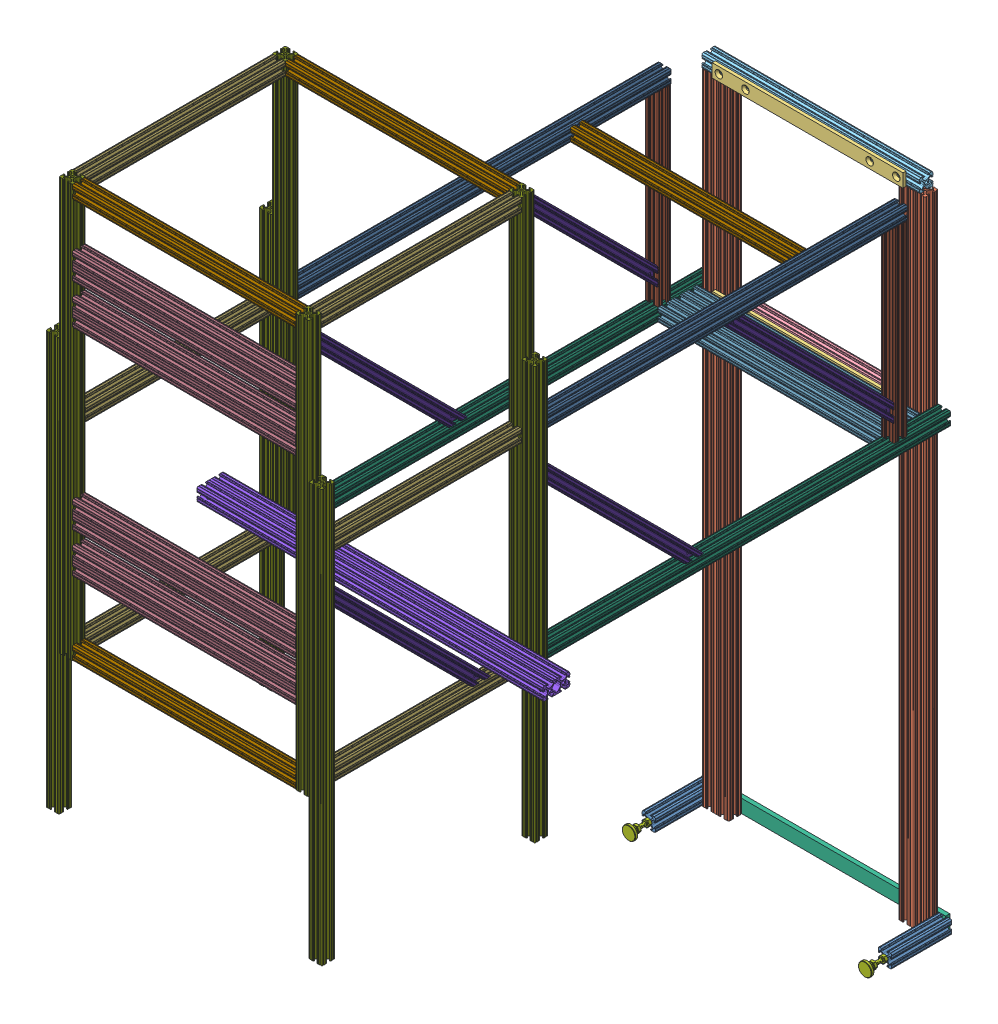
SolidWorks assembly FEA - _Tow System Assy V1.1, configuration Default. Lengths in mm.
Overall size (660.4 1633.42 1235.21).
46 component instances, 17 part files, 141 mates.
Components (placement in the parent):
- FEA - 8020 -1inch - 0 ft 4.5 in-1: FEA - 8020 -1inch - 0 ft 4.5 in [47065T122] at (0 -1222.37 -954.22) x (-1 0 0) z (0 0 1) size (25.4 25.4 114.3)
- FEA - 8020 -1inch - 0 ft 4.5 in-2: FEA - 8020 -1inch - 0 ft 4.5 in [47065T122] at (450.85 -1222.37 -954.22) x (-1 0 0) z (0 0 1) size (25.4 25.4 114.3)
- FEA - 47065T125_2inch - 4 ft-1: FEA - 47065T125_2inch - 4 ft [47065T125] at (38.1 -625.47 -998.67) x (1 0 0) z (0 1 0) size (50.8 25.4 1219.2)
- FEA - 47065T125_2inch - 4 ft-2: FEA - 47065T125_2inch - 4 ft [47065T125] at (412.75 -625.47 -998.67) x (1 0 0) z (0 1 0) size (50.8 25.4 1219.2)
- FEA - 1614T644_1in x 364mm Aluminium bar - 5_16 thick-1: FEA - 1614T644_1in x 364mm Aluminium bar - 5_16 thick [1614T644] at (220.1 -381 -982.97) x (0 -1 0) z (-1 0 0) size (25.4 6 364)
- FEA - 1614T644_1in x 364mm Aluminium bar - 5_16 thick-2: FEA - 1614T644_1in x 364mm Aluminium bar - 5_16 thick [1614T644] at (220.1 -3.17 -982.97) x (0 1 0) z (1 0 0) size (25.4 6 364)
- FEA - 8020 -1inch - 1 ft 0.25-3: FEA - 8020 -1inch - 1 ft 0.25 [47065T122] at (219.075 -381 -998.67) x (0 0 -1) z (1 0 0) size (25.4 25.4 311.15)
- FEA - 8020 -1inch - 415mm-1: FEA - 8020 -1inch - 415mm [47065T122] at (220.2 -3.17 -998.67) x (0 0 -1) z (1 0 0) size (25.4 25.4 415)
- FEA - 1614T644_1in x 465mm Aluminium bar - 5_16 thick-1: FEA - 1614T644_1in x 465mm Aluminium bar - 5_16 thick [1614T644] at (219.8 -1222.37 -1015.3388) x (0 -1 0) z (-1 0 0) size (25.4 7.94 465)
- FEA - 6111K115_SS Leveling Foot-3: FEA - 6111K115_SS Leveling Foot [6111K115] at (0 -1222.37 -858.4408) x (-0.866025 0.5 0) z (-0.5 -0.866025 0) size (25.4 81.68 25.4)
- FEA - 6111K115_SS Leveling Foot-4: FEA - 6111K115_SS Leveling Foot [6111K115] at (450.85 -1222.37 -858.4408) x (0.866025 0.5 0) z (-0.5 0.866025 0) size (25.4 81.68 25.4)
- FEA - 8020 - 2inch - 2 ft 2 in-1: FEA - 8020 - 2inch - 2 ft 2 in [47065T213] at (225.425 -355.6 -165.1) x (0 0 1) z (-1 0 0) size (50.8 25.4 660.4)
- FEA - 8020 -1inch - 1 ft 4.75 in-9: FEA - 8020 -1inch - 1 ft 4.75 in [47065T122] at (225.425 -381 203.2) x (0 -1 0) z (1 0 0) size (25.4 25.4 425.45)
- FEA - 8020 -1inch - 2 ft 4 in-13: FEA - 8020 -1inch - 2 ft 4 in [47065T122] at (0 0 -571.5) x (-1 0 0) z (0 0 -1) size (25.4 25.4 711.2)
- FEA - 8020 -1inch - 2 ft 4 in-14: FEA - 8020 -1inch - 2 ft 4 in [47065T122] at (450.85 0 -571.5) x (-1 0 0) z (0 0 -1) size (25.4 25.4 711.2)
- FEA - 8020 -1inch - 1 ft 2 in-1: FEA - 8020 -1inch - 1 ft 2 in [47065T122] at (0 -190.5 -914.4) x (1 0 0) z (0 1 0) size (25.4 25.4 355.6)
- FEA - 8020 -1inch - 1 ft 3 in-2: FEA - 8020 -1inch - 1 ft 3 in [47065T122] at origin size (25.4 25.4 381)
- FEA - 8020 -1inch - 1 ft 3 in-3: FEA - 8020 -1inch - 1 ft 3 in [47065T122] at (0 -381 0) size (25.4 25.4 381)
- FEA - 8020 -1inch - 1 ft 2 in-2: FEA - 8020 -1inch - 1 ft 2 in [47065T122] at (450.85 -190.5 -914.4) x (1 0 0) z (0 1 0) size (25.4 25.4 355.6)
- FEA - 8020 -1inch - 1 ft 3 in-4: FEA - 8020 -1inch - 1 ft 3 in [47065T122] at (450.85 -381 0) size (25.4 25.4 381)
- FEA - 8020 -1inch - 1 ft 3 in-6: FEA - 8020 -1inch - 1 ft 3 in [47065T122] at (450.85 0 0) size (25.4 25.4 381)
- FEA - 8020 -1inch - 1 ft 4.75 in-18: FEA - 8020 -1inch - 1 ft 4.75 in [47065T122] at (225.425 0 -747.4605) x (0 -1 0) z (1 0 0) size (25.4 25.4 425.45)
- FEA - 8020 - 2inch - 1 ft 4.75 in-9: FEA - 8020 - 2inch - 1 ft 4.75 in [47065T213] at (225.425 258.3 203.2) x (0 -1 0) z (1 0 0) size (50.8 25.4 425.45)
- FEA - 47065T512_8020 - 3inch - 1 ft 4.75 in-1: FEA - 47065T512_8020 - 3inch - 1 ft 4.75 in [47065T512] at (225.425 -381 -939.8) x (0 -1 0) z (-1 0 0) size (25.4 76.2 425.45)
- FEA - 8020 -1inch - 2 ft 8 inches-1: FEA - 8020 -1inch - 2 ft 8 inches [47065T122] at (0 -381 -612.635) size (25.4 25.4 793.47)
- FEA - 8020 -1inch - 2 ft 8 inches-2: FEA - 8020 -1inch - 2 ft 8 inches [47065T122] at (450.85 -381 -612.635) size (25.4 25.4 793.47)
- FEA - 8020 -1inch - 2 ft 7 inches-1: FEA - 8020 -1inch - 2 ft 7 inches [47065T122] at (0 0 -203.2) x (-1 0 0) z (0 1 0) size (25.4 25.4 787.4)
- FEA - 8020 -1inch - 2 ft 7 inches-2: FEA - 8020 -1inch - 2 ft 7 inches [47065T122] at (0 0 203.2) x (-1 0 0) z (0 1 0) size (25.4 25.4 787.4)
- FEA - 8020 -1inch - 2 ft 7 inches-3: FEA - 8020 -1inch - 2 ft 7 inches [47065T122] at (-25.4 -266.7 -203.2) x (-1 0 0) z (0 1 0) size (25.4 25.4 787.4)
- FEA - 8020 -1inch - 1 ft 3 in-7: FEA - 8020 -1inch - 1 ft 3 in [47065T122] at (0 381 0) size (25.4 25.4 381)
- FEA - 8020 -1inch - 2 ft 7 inches-6: FEA - 8020 -1inch - 2 ft 7 inches [47065T122] at (450.85 0 -203.2) x (-1 0 0) z (0 1 0) size (25.4 25.4 787.4)
- FEA - 8020 -1inch - 1 ft 4.75 in-19: FEA - 8020 -1inch - 1 ft 4.75 in [47065T122] at (225.425 381 -203.2) x (0 -1 0) z (1 0 0) size (25.4 25.4 425.45)
- FEA - 8020 -1inch - 1 ft 4.75 in-20: FEA - 8020 -1inch - 1 ft 4.75 in [47065T122] at (225.425 381 203.2) x (0 -1 0) z (1 0 0) size (25.4 25.4 425.45)
- FEA - 47065T701_45 Brace - 18 in-12: FEA - 47065T701_45 Brace - 18 in [47065T701] at (450.85 -215.6355 -368.5645) x (1 0 0) z (0 0.707107 0.707107) size (25.4 25.56 457.2)
- FEA - 8020 -1inch - 2 ft 7 inches-8: FEA - 8020 -1inch - 2 ft 7 inches [47065T122] at (450.85 0 203.2) x (-1 0 0) z (0 1 0) size (25.4 25.4 787.4)
- FEA - 8020 -1inch - 1 ft 3 in-8: FEA - 8020 -1inch - 1 ft 3 in [47065T122] at (450.85 381 0) size (25.4 25.4 381)
- FEA - 8020 -1inch - 2 ft 7 inches-9: FEA - 8020 -1inch - 2 ft 7 inches [47065T122] at (476.25 -266.7 203.2) x (-1 0 0) z (0 1 0) size (25.4 25.4 787.4)
- FEA - 8020 -1inch - 2 ft 7 inches-10: FEA - 8020 -1inch - 2 ft 7 inches [47065T122] at (476.25 -266.7 -203.2) x (-1 0 0) z (0 1 0) size (25.4 25.4 787.4)
- FEA - 8020 -1inch - 2 ft 7 inches-11: FEA - 8020 -1inch - 2 ft 7 inches [47065T122] at (-25.4 -266.7 203.2) x (-1 0 0) z (0 1 0) size (25.4 25.4 787.4)
- FEA - 8020 - 2inch - 1 ft 4.75 in-10: FEA - 8020 - 2inch - 1 ft 4.75 in [47065T213] at (225.425 -152.7 203.2) x (0 -1 0) z (1 0 0) size (50.8 25.4 425.45)
- FEA - 8020 - 2inch - 1 ft 4.75 in-11: FEA - 8020 - 2inch - 1 ft 4.75 in [47065T213] at (225.425 -228.9 203.2) x (0 -1 0) z (1 0 0) size (50.8 25.4 425.45)
- FEA - 8020 - 2inch - 1 ft 4.75 in-12: FEA - 8020 - 2inch - 1 ft 4.75 in [47065T213] at (225.425 182.1 203.2) x (0 -1 0) z (1 0 0) size (50.8 25.4 425.45)
- FEA - 47065T701_45 Brace - 18 in-15: FEA - 47065T701_45 Brace - 18 in [47065T701] at (0 -215.6355 -368.5645) x (1 0 0) z (0 0.707107 0.707107) size (25.4 25.56 457.2)
- FEA - 47065T701_45 Brace - 18 in-16: FEA - 47065T701_45 Brace - 18 in [47065T701] at (450.85 -215.6355 37.8355) x (1 0 0) z (0 0.707107 0.707107) size (25.4 25.56 457.2)
- FEA - 47065T701_45 Brace - 18 in-17: FEA - 47065T701_45 Brace - 18 in [47065T701] at (0 -165.3645 -749.0355) x (-1 0 0) z (0 0.707107 0.707107) size (25.4 25.56 457.2)
- FEA - 47065T701_45 Brace - 18 in-18: FEA - 47065T701_45 Brace - 18 in [47065T701] at (450.85 -165.3645 -749.0355) x (-1 0 0) z (0 0.707107 0.707107) size (25.4 25.56 457.2)
Mates (geometry in assembly coordinates):
- Concentric12: concentric anti-aligned: circle of L Bracket Spacer-3; circle of 1 inch x 2 inch L bracket-6
- Concentric13: concentric anti-aligned: circle of L Bracket Spacer-3; circle of 1 inch x 2 inch L bracket-6
- Coincident329: coincident anti-aligned: plane of L Bracket Spacer-3 through (558.333 1657.0643 1927.6829) normal (-0.646537 0.60797 -0.460828); plane of 1 inch x 2 inch L bracket-6 through (600.4865 1679.6629 1898.3561) normal (0.646537 -0.60797 0.460828)
- Concentric15: concentric anti-aligned: circle of L Bracket Spacer-4; circle of 1 inch x 2 inch L bracket-5
- Concentric16: concentric anti-aligned: circle of L Bracket Spacer-4; circle of 1 inch x 2 inch L bracket-5
- Coincident330: coincident anti-aligned: plane of L Bracket Spacer-4 through (764.4476 1681.6047 1670.8822) normal (-0.646537 0.60797 -0.460828); plane of 1 inch x 2 inch L bracket-5 through (765.1438 1682.8596 1671.5609) normal (0.646537 -0.60797 0.460828)
- Coincident668: coincident anti-aligned: plane of 8020 -1inch - 2 ft 4 in-13 through (12.7 9.5504 -927.1) normal (1 0 0); plane of 8020 -1inch - 1 ft 4.75 in-18 through (12.7 6.4164 -738.0506) normal (-1 0 0)
- Coincident669: coincident aligned: plane of 8020 -1inch - 2 ft 4 in-13 through (6.3331 12.7 -927.1) normal (0 1 0); plane of 8020 -1inch - 1 ft 4.75 in-18 through (438.15 12.7 -741.1274) normal (0 1 0)
- Coincident682: coincident aligned: plane of 8020 -1inch - 0 ft 4.5 in-1 through (-9.5504 -1235.07 -897.07) normal (0 -1 0); plane of 47065T125_2inch - 4 ft-1 through (56.6251 -1235.07 -1011.37) normal (0 -1 0)
- Coincident683: coincident aligned: plane of 8020 -1inch - 0 ft 4.5 in-1 through (6.4164 -1212.9602 -1011.37) normal (0 0 -1); plane of 47065T125_2inch - 4 ft-1 through (60.3504 -15.87 -1011.37) normal (0 0 -1)
- Coincident685: coincident anti-aligned: plane of 8020 -1inch - 0 ft 4.5 in-1 through (12.7 -1231.9204 -897.07) normal (1 0 0); plane of 47065T125_2inch - 4 ft-1 through (12.7 -15.87 -992.3369) normal (-1 0 0)
- Coincident696: coincident aligned: plane of 8020 -1inch - 0 ft 4.5 in-2 through (441.2996 -1235.07 -897.07) normal (0 -1 0); plane of 47065T125_2inch - 4 ft-2 through (431.2751 -1235.07 -1011.37) normal (0 -1 0)
- Coincident700: coincident aligned: plane of 8020 -1inch - 0 ft 4.5 in-2 through (457.2664 -1212.9602 -1011.37) normal (0 0 -1); plane of 47065T125_2inch - 4 ft-2 through (414.8836 -15.87 -1011.37) normal (0 0 -1)
- Coincident701: coincident anti-aligned: plane of 8020 -1inch - 0 ft 4.5 in-2 through (438.15 -1212.8196 -897.07) normal (-1 0 0); plane of 47065T125_2inch - 4 ft-2 through (438.15 -15.87 -1005.0032) normal (1 0 0)
- Parallel16: parallel aligned: plane of 47065T125_2inch - 4 ft-1 through (19.0669 -15.87 -1011.37) normal (0 0 -1); plane of 47065T125_2inch - 4 ft-2 through (393.7169 -15.87 -1011.37) normal (0 0 -1)
- Coincident831: coincident aligned: plane of 47065T125_2inch - 4 ft-1 through (56.6251 -15.87 -1011.37) normal (0 1 0); plane of 47065T125_2inch - 4 ft-2 through (431.2751 -15.87 -1011.37) normal (0 1 0)
- Coincident862: coincident aligned: plane of 8020 -1inch - 1 ft 4.75 in-9 through (438.15 -368.3 193.6496) normal (0 1 0); plane of 8020 -1inch - 1 ft 3 in-3 through (-6.3331 -368.3 190.5) normal (0 1 0)
- Coincident869: coincident aligned: plane of 8020 -1inch - 1 ft 4.75 in-9 through (438.15 -368.3 209.5331) normal (0 1 0); plane of 8020 -1inch - 1 ft 3 in-4 through (460.4004 -368.3 190.5) normal (0 1 0)
- Coincident880: coincident anti-aligned: plane of 8020 -1inch - 1 ft 2 in-1 through (-9.5504 -12.7 -901.7) normal (0 0 1); plane of 47065T701_45 Brace - 18 in-8 through (12.7 -300.0684 -901.7) normal (0 0 -1)
- Coincident881: coincident anti-aligned: plane of 8020 -1inch - 2 ft 4 in-13 through (-6.3331 -12.7 -927.1) normal (0 -1 0); plane of 47065T701_45 Brace - 18 in-8 through (12.7 -12.7 -614.3316) normal (0 1 0)
- Coincident883: coincident anti-aligned: plane of 8020 -1inch - 1 ft 2 in-2 through (457.1831 -12.7 -901.7) normal (0 0 1); plane of 47065T701_45 Brace - 18 in-9 through (463.55 -300.0684 -901.7) normal (0 0 -1)
- Coincident884: coincident aligned: plane of 8020 -1inch - 1 ft 2 in-2 through (463.55 -12.7 -904.8496) normal (1 0 0); plane of 47065T701_45 Brace - 18 in-9 through (463.55 -10.473 -580.6378) normal (1 0 0)
- Coincident885: coincident anti-aligned: plane of 8020 -1inch - 2 ft 4 in-14 through (460.4004 -12.7 -927.1) normal (0 -1 0); plane of 47065T701_45 Brace - 18 in-9 through (463.55 -12.7 -614.3316) normal (0 1 0)
- Coincident886: coincident anti-aligned: plane of 8020 -1inch - 2 ft 4 in-13 through (9.5504 -12.7 -927.1) normal (0 -1 0); plane of 8020 -1inch - 1 ft 2 in-1 through (-6.4164 -12.7 -904.9902) normal (0 1 0)
- Coincident887: coincident anti-aligned: plane of 8020 -1inch - 2 ft 4 in-14 through (460.4004 -12.7 -927.1) normal (0 -1 0); plane of 8020 -1inch - 1 ft 2 in-2 through (444.4336 -12.7 -904.9902) normal (0 1 0)
- Concentric28: concentric: circle of 6111K115_SS Leveling Foot-3; circle of 8020 -1inch - 0 ft 4.5 in-1
- Coincident943: coincident: plane of 8020 -1inch - 0 ft 4.5 in-1 through (6.4164 -1212.9602 -897.07) normal (0 0 1); plane of 6111K115_SS Leveling Foot-3 through (-3.2079 -1227.9263 -897.07) normal (0 0 -1)
- Concentric29: concentric: circle of 6111K115_SS Leveling Foot-4; circle of 8020 -1inch - 0 ft 4.5 in-2
- Coincident944: coincident: plane of 8020 -1inch - 0 ft 4.5 in-2 through (457.2664 -1212.9602 -897.07) normal (0 0 1); plane of 6111K115_SS Leveling Foot-4 through (447.7293 -1216.7643 -897.07) normal (0 0 -1)
- Coincident1026: coincident aligned: plane of 47065T125_2inch - 4 ft-1 through (60.3504 -15.87 -1011.37) normal (0 0 -1); plane of 8020 -1inch - 1 ft 0.25-3 through (374.65 -390.5504 -1011.37) normal (0 0 -1)
- Coincident1027: coincident anti-aligned: plane of 47065T125_2inch - 4 ft-1 through (63.5 -15.87 -1005.0032) normal (1 0 0); plane of 8020 -1inch - 1 ft 0.25-3 through (63.5 -390.4098 -992.2536) normal (-1 0 0)
- Distance42: distance = 25.4 mm aligned: plane of 1614T644_1in x 364mm Aluminium bar - 5_16 thick-1 through (38.1 -381 -982.97) normal (-1 0 0); plane of 8020 -1inch - 1 ft 0.25-3 through (63.5 -390.4098 -992.2536) normal (-1 0 0)
- Distance44: distance = 25.4 mm anti-aligned: plane of 1614T644_1in x 364mm Aluminium bar - 5_16 thick-2 through (38.1 -3.17 -982.97) normal (-1 0 0); plane of 47065T125_2inch - 4 ft-1 through (63.5 -15.87 -989.1196) normal (1 0 0)
- Coincident1083: coincident anti-aligned: plane of 47065T125_2inch - 4 ft-1 through (56.6251 -15.87 -1011.37) normal (0 1 0); plane of 8020 -1inch - 415mm-1 through (427.7 -15.87 -989.1196) normal (0 -1 0)
- Coincident1085: coincident aligned: plane of 47065T125_2inch - 4 ft-1 through (19.0669 -15.87 -1011.37) normal (0 0 -1); plane of 8020 -1inch - 415mm-1 through (427.7 3.1631 -1011.37) normal (0 0 -1)
- Distance45: distance = 352.43 mm anti-aligned: plane of 8020 -1inch - 1 ft 0.25-3 through (374.65 -368.3 -992.3369) normal (0 1 0); plane of 8020 -1inch - 415mm-1 through (427.7 -15.87 -1005.0031) normal (0 -1 0)
- Coincident1107: coincident anti-aligned: plane of 8020 -1inch - 1 ft 2 in-1 through (12.7 -12.7 -920.7331) normal (1 0 0); plane of 47065T512_8020 - 3inch - 1 ft 4.75 in-1 through (12.7 -370.9416 -901.7) normal (-1 0 0)
- Coincident1108: coincident anti-aligned: plane of 8020 -1inch - 1 ft 2 in-1 through (-6.4164 -368.3 -904.9902) normal (0 -1 0); plane of 47065T512_8020 - 3inch - 1 ft 4.75 in-1 through (12.7 -368.3 -946.1246) normal (0 1 0)
- Coincident1109: coincident aligned: plane of 8020 -1inch - 2 ft 4 in-13 through (-12.7 -9.5504 -927.1) normal (-1 0 0); plane of 8020 -1inch - 1 ft 2 in-1 through (-12.7 -12.7 -923.9504) normal (-1 0 0)
- Coincident1111: coincident aligned: plane of 8020 -1inch - 1 ft 2 in-1 through (6.3331 -12.7 -901.7) normal (0 0 1); plane of 47065T512_8020 - 3inch - 1 ft 4.75 in-1 through (12.7 -390.5504 -901.7) normal (0 0 1)
- Coincident1114: coincident anti-aligned: plane of 8020 -1inch - 1 ft 2 in-1 through (-6.4164 -368.3 -904.9902) normal (0 -1 0); plane of 8020 -1inch - 2 ft 8 inches-1 through (-6.3331 -368.3 -215.9) normal (0 1 0)
- Tangent1: tangent: curve of 47065T701_45 Brace - 18 in-1; plane of 8020 -1inch - 2 ft 8 inches-1 through (-6.3331 -368.3 -215.9) normal (0 1 0)
- Coincident1116: coincident aligned: plane of 8020 -1inch - 1 ft 2 in-1 through (-12.7 -12.7 -908.0669) normal (-1 0 0); plane of 47065T701_45 Brace - 18 in-8 through (-12.7 3.0333 -594.1441) normal (-1 0 0)
- Coincident1128: coincident anti-aligned: plane of 8020 -1inch - 0 ft 4.5 in-1 through (6.4164 -1212.9602 -1011.37) normal (0 0 -1); plane of 1614T644_1in x 465mm Aluminium bar - 5_16 thick-1 through (-12.7 -1235.07 -1011.37) normal (0 0 1)
- Coincident1129: coincident: plane of 8020 -1inch - 0 ft 4.5 in-1 through (-9.5504 -1235.07 -897.07) normal (0 -1 0); line of 1614T644_1in x 465mm Aluminium bar - 5_16 thick-1 through (-12.7 -1235.07 -1019.3075) axis (1 0 0)
- Coincident1130: coincident aligned: plane of 8020 -1inch - 0 ft 4.5 in-1 through (-12.7 -1228.7031 -897.07) normal (-1 0 0); plane of 1614T644_1in x 465mm Aluminium bar - 5_16 thick-1 through (-12.7 -1222.37 -1015.3388) normal (-1 0 0)
- Coincident1131: coincident anti-aligned: circle of 8020 -1inch - 1 ft 2 in-2; plane of 8020 -1inch - 2 ft 8 inches-2 through (460.4004 -368.3 -215.9) normal (0 1 0)
- Coincident1132: coincident aligned: plane of 8020 -1inch - 1 ft 2 in-2 through (463.55 -12.7 -920.7331) normal (1 0 0); plane of 8020 -1inch - 2 ft 8 inches-2 through (463.55 -374.6669 -215.9) normal (1 0 0)
- Coincident1133: coincident aligned: circle of 8020 -1inch - 2 ft 8 inches-1; plane of 8020 -1inch - 2 ft 8 inches-2 through (444.4336 -390.4098 -1009.37) normal (0 0 -1)
- Coincident1134: coincident aligned: plane of 8020 -1inch - 2 ft 4 in-14 through (463.55 -6.3331 -927.1) normal (1 0 0); plane of 8020 -1inch - 1 ft 2 in-2 through (463.55 -12.7 -904.8496) normal (1 0 0)
- Coincident1144: coincident aligned: plane of 8020 -1inch - 2 ft 4 in-14 through (441.2996 12.7 -927.1) normal (0 1 0); plane of 8020 -1inch - 1 ft 4.75 in-18 through (438.15 12.7 -757.0109) normal (0 1 0)
- Coincident1147: coincident aligned: plane of 8020 -1inch - 2 ft 4 in-13 through (-9.5504 12.7 -927.1) normal (0 1 0); plane of 8020 -1inch - 1 ft 3 in-2 through (-6.3331 12.7 190.5) normal (0 1 0)
- Coincident1148: coincident aligned: plane of 8020 -1inch - 2 ft 8 inches-1 through (-9.5504 -393.7 -215.9) normal (0 -1 0); plane of 8020 -1inch - 2 ft 7 inches-1 through (6.4164 -393.7 -212.6098) normal (0 -1 0)
- Coincident1149: coincident aligned: plane of 8020 -1inch - 2 ft 8 inches-1 through (-12.7 -371.4496 -215.9) normal (-1 0 0); plane of 8020 -1inch - 2 ft 7 inches-1 through (-12.7 393.7 -212.7504) normal (-1 0 0)
- Coincident1153: coincident anti-aligned: plane of 8020 -1inch - 1 ft 4.75 in-9 through (438.15 -374.6669 190.5) normal (0 0 -1); plane of 8020 -1inch - 1 ft 3 in-3 through (-6.4164 -390.4098 190.5) normal (0 0 1)
- Coincident1154: coincident anti-aligned: plane of 8020 -1inch - 1 ft 4.75 in-9 through (12.7 -374.5836 212.6098) normal (-1 0 0); plane of 8020 -1inch - 1 ft 3 in-3 through (12.7 -374.6669 190.5) normal (1 0 0)
- Coincident1158: coincident anti-aligned: plane of 8020 -1inch - 2 ft 8 inches-1 through (-6.4164 -390.4098 -215.9) normal (0 0 1); plane of 8020 -1inch - 2 ft 7 inches-1 through (-6.3331 393.7 -215.9) normal (0 0 -1)
- Coincident1159: coincident: plane of 8020 -1inch - 1 ft 3 in-3 through (-12.7 -371.4496 190.5) normal (-1 0 0); line of 8020 -1inch - 2 ft 8 inches-1 through (-12.7 -371.4496 -215.9) axis (0 0 -1)
- Coincident1161: coincident aligned: plane of 8020 -1inch - 2 ft 4 in-13 through (-12.7 6.3331 -927.1) normal (-1 0 0); plane of 47065T701_45 Brace - 18 in-1 through (-12.7 -47.2378 -213.673) normal (-1 0 0)
- Coincident1162: coincident aligned: plane of 8020 -1inch - 2 ft 4 in-13 through (-12.7 6.3331 -927.1) normal (-1 0 0); plane of 8020 -1inch - 1 ft 3 in-2 through (-12.7 9.5504 190.5) normal (-1 0 0)
- Coincident1164: coincident anti-aligned: plane of 47065T512_8020 - 3inch - 1 ft 4.75 in-1 through (12.7 -370.9416 -901.7) normal (-1 0 0); plane of 8020 -1inch - 2 ft 8 inches-1 through (12.7 -374.6669 -215.9) normal (1 0 0)
- Coincident1165: coincident aligned: plane of 8020 -1inch - 2 ft 4 in-13 through (6.4164 -9.4098 -215.9) normal (0 0 1); plane of 8020 -1inch - 2 ft 4 in-14 through (457.2664 -9.4098 -215.9) normal (0 0 1)
- Coincident1166: coincident aligned: plane of 8020 -1inch - 1 ft 3 in-3 through (-9.5504 -393.7 190.5) normal (0 -1 0); plane of 8020 -1inch - 2 ft 7 inches-2 through (6.4164 -393.7 193.7902) normal (0 -1 0)
- Coincident1167: coincident aligned: plane of 8020 -1inch - 1 ft 4.75 in-9 through (438.15 -387.3331 215.9) normal (0 0 1); plane of 8020 -1inch - 2 ft 7 inches-2 through (-9.5504 393.7 215.9) normal (0 0 1)
- Coincident1168: coincident anti-aligned: plane of 8020 -1inch - 1 ft 4.75 in-9 through (12.7 -374.5836 212.6098) normal (-1 0 0); plane of 8020 -1inch - 2 ft 7 inches-2 through (12.7 393.7 212.7504) normal (1 0 0)
- Coincident1169: coincident anti-aligned: plane of 47065T701_45 Brace - 18 in-1 through (-12.7 -80.9316 -215.9) normal (0 0 1); plane of 8020 -1inch - 2 ft 7 inches-1 through (-6.3331 393.7 -215.9) normal (0 0 -1)
- Coincident1170: coincident anti-aligned: plane of 8020 - 2inch - 1 ft 4.75 in-9 through (12.7 239.7749 190.5) normal (-1 0 0); plane of 8020 -1inch - 2 ft 7 inches-2 through (12.7 393.7 212.7504) normal (1 0 0)
- Coincident1171: coincident aligned: plane of 8020 - 2inch - 1 ft 4.75 in-9 through (438.15 280.5504 215.9) normal (0 0 1); plane of 8020 -1inch - 2 ft 7 inches-2 through (6.3331 393.7 215.9) normal (0 0 1)
- Coincident1175: coincident anti-aligned: plane of 8020 -1inch - 2 ft 7 inches-2 through (12.7 393.7 212.7504) normal (1 0 0); plane of 8020 - 2inch - 1 ft 4.75 in-12 through (12.7 163.5749 190.5) normal (-1 0 0)
- Coincident1176: coincident aligned: plane of 8020 -1inch - 2 ft 7 inches-2 through (6.3331 393.7 215.9) normal (0 0 1); plane of 8020 - 2inch - 1 ft 4.75 in-12 through (438.15 204.3504 215.9) normal (0 0 1)
- Coincident1178: coincident aligned: plane of 8020 -1inch - 1 ft 3 in-2 through (-6.4164 -9.4098 -190.5) normal (0 0 -1); plane of 8020 -1inch - 1 ft 3 in-3 through (-6.4164 -390.4098 -190.5) normal (0 0 -1)
- Coincident1179: coincident anti-aligned: plane of 8020 -1inch - 2 ft 7 inches-1 through (-9.5504 393.7 -190.5) normal (0 0 1); plane of 8020 -1inch - 1 ft 3 in-7 through (-6.4164 371.5902 -190.5) normal (0 0 -1)
- Coincident1180: coincident aligned: plane of 8020 -1inch - 2 ft 7 inches-1 through (-12.7 393.7 -196.8669) normal (-1 0 0); plane of 8020 -1inch - 1 ft 3 in-7 through (-12.7 390.5504 190.5) normal (-1 0 0)
- Coincident1181: coincident aligned: plane of 8020 -1inch - 2 ft 7 inches-1 through (6.4164 393.7 -212.6098) normal (0 1 0); plane of 8020 -1inch - 1 ft 3 in-7 through (-6.3331 393.7 190.5) normal (0 1 0)
- Coincident1216: coincident aligned: plane of 8020 - 2inch - 1 ft 4.75 in-10 through (12.7 -171.2251 190.5) normal (-1 0 0); plane of 8020 - 2inch - 1 ft 4.75 in-11 through (12.7 -247.4251 190.5) normal (-1 0 0)
- Coincident1224: coincident aligned: line of 8020 -1inch - 1 ft 3 in-3 through (-6.3331 -368.3 190.5) axis (0 0 -1); line of 8020 -1inch - 2 ft 8 inches-1 through (-6.3331 -368.3 -215.9) axis (0 0 -1)
- Coincident1225: coincident aligned: plane of 8020 -1inch - 2 ft 4 in-13 through (6.4164 -9.4098 -215.9) normal (0 0 1); plane of 8020 -1inch - 2 ft 8 inches-2 through (444.4336 -390.4098 -215.9) normal (0 0 1)
- Coincident1226: coincident anti-aligned: plane of 47065T701_45 Brace - 18 in-2 through (438.15 -368.3 -96.8684) normal (0 -1 0); plane of 8020 -1inch - 2 ft 8 inches-2 through (460.4004 -368.3 -215.9) normal (0 1 0)
- Coincident1233: coincident aligned: plane of 8020 - 2inch - 1 ft 4.75 in-10 through (438.15 -155.8496 215.9) normal (0 0 1); plane of 8020 - 2inch - 1 ft 4.75 in-11 through (438.15 -206.6496 215.9) normal (0 0 1)
- Coincident1235: coincident aligned: plane of 8020 - 2inch - 1 ft 4.75 in-9 through (12.7 239.7749 190.5) normal (-1 0 0); plane of 8020 - 2inch - 1 ft 4.75 in-10 through (12.7 -171.2251 190.5) normal (-1 0 0)
- Coincident1245: coincident aligned: plane of 8020 -1inch - 2 ft 7 inches-3 through (-18.9836 127 -212.6098) normal (0 1 0); plane of 8020 -1inch - 2 ft 7 inches-5 through (-18.9836 127 193.7902) normal (0 1 0)
- Distance48: distance = 140 mm aligned: plane of 8020 - 2inch - 1 ft 4.75 in-10 through (438.15 -127.3 193.6496) normal (0 1 0); plane of 8020 -1inch - 2 ft 3 in-14 through (441.2996 12.7 -927.1) normal (0 1 0)
- Coincident1252: coincident aligned: plane of 8020 -1inch - 2 ft 4 in-14 through (463.55 9.5504 -927.1) normal (1 0 0); plane of 8020 -1inch - 1 ft 3 in-6 through (463.55 6.3331 190.5) normal (1 0 0)
- Coincident1255: coincident: plane of 8020 -1inch - 1 ft 3 in-3 through (-6.4164 -390.4098 -190.5) normal (0 0 -1); line of 8020 -1inch - 2 ft 7 inches-1 through (-9.5504 393.7 -190.5) axis (0 -1 0)
- Coincident1256: coincident anti-aligned: plane of 8020 -1inch - 1 ft 4.75 in-9 through (438.15 -374.6669 190.5) normal (0 0 -1); plane of 8020 -1inch - 1 ft 3 in-4 through (444.4336 -390.4098 190.5) normal (0 0 1)
- Coincident1257: coincident anti-aligned: plane of 8020 -1inch - 1 ft 4.75 in-9 through (438.15 -374.5836 212.6098) normal (1 0 0); plane of 8020 -1inch - 1 ft 3 in-4 through (438.15 -371.4496 190.5) normal (-1 0 0)
- Coincident1258: coincident aligned: plane of 8020 -1inch - 1 ft 3 in-4 through (444.4336 -390.4098 190.5) normal (0 0 1); plane of 8020 -1inch - 1 ft 3 in-6 through (444.4336 -9.4098 190.5) normal (0 0 1)
- Coincident1260: coincident aligned: plane of 8020 -1inch - 1 ft 3 in-4 through (463.55 -374.6669 190.5) normal (1 0 0); plane of 8020 -1inch - 2 ft 8 inches-2 through (463.55 -374.6669 -215.9) normal (1 0 0)
- Coincident1261: coincident: line of 8020 -1inch - 1 ft 3 in-4 through (463.55 -371.4496 190.5) axis (0 0 -1); plane of 47065T701_45 Brace - 18 in-2 through (463.55 -60.7441 206.2333) normal (1 0 0)
- Coincident1262: coincident aligned: plane of 8020 -1inch - 1 ft 3 in-4 through (444.4336 -390.4098 190.5) normal (0 0 1); plane of 47065T701_45 Brace - 18 in-2 through (438.15 -80.9316 190.5) normal (0 0 1)
- Coincident1263: coincident aligned: plane of 8020 -1inch - 2 ft 4 in-14 through (457.1831 12.7 -927.1) normal (0 1 0); plane of 8020 -1inch - 1 ft 3 in-6 through (460.4004 12.7 190.5) normal (0 1 0)
- Coincident1265: coincident: line of 8020 -1inch - 2 ft 8 inches-2 through (463.55 -371.4496 -215.9) axis (0 0 -1); plane of 47065T701_45 Brace - 18 in-12 through (463.55 -49.5128 -211.398) normal (1 0 0)
- Coincident1266: coincident anti-aligned: plane of 8020 -1inch - 2 ft 8 inches-2 through (460.4004 -368.3 -215.9) normal (0 1 0); plane of 47065T701_45 Brace - 18 in-12 through (438.15 -368.3 -503.2684) normal (0 -1 0)
- Coincident1267: coincident aligned: plane of 8020 -1inch - 2 ft 8 inches-2 through (444.4336 -390.4098 -215.9) normal (0 0 1); plane of 47065T701_45 Brace - 18 in-12 through (438.15 -80.9316 -215.9) normal (0 0 1)
- Distance49: distance = 110 mm aligned: plane of 8020 - 2inch - 1 ft 4.75 in-9 through (438.15 283.7 209.5331) normal (0 1 0); plane of 8020 -1inch - 2 ft 7 inches-2 through (6.4164 393.7 193.7902) normal (0 1 0)
- Coincident1269: coincident anti-aligned: plane of 8020 -1inch - 1 ft 3 in-7 through (12.7 387.3331 190.5) normal (1 0 0); plane of 8020 -1inch - 1 ft 4.75 in-20 through (12.7 387.4164 212.6098) normal (-1 0 0)
- Coincident1270: coincident aligned: plane of 8020 -1inch - 1 ft 3 in-7 through (9.5504 393.7 190.5) normal (0 1 0); plane of 8020 -1inch - 1 ft 4.75 in-20 through (438.15 393.7 209.5331) normal (0 1 0)
- Coincident1272: coincident anti-aligned: plane of 8020 -1inch - 1 ft 3 in-7 through (-6.4164 371.5902 190.5) normal (0 0 1); plane of 8020 -1inch - 1 ft 4.75 in-20 through (438.15 387.3331 190.5) normal (0 0 -1)
- Coincident1273: coincident anti-aligned: plane of 8020 -1inch - 1 ft 3 in-7 through (-6.4164 371.5902 -190.5) normal (0 0 -1); plane of 8020 -1inch - 1 ft 4.75 in-19 through (438.15 390.5504 -190.5) normal (0 0 1)
- Coincident1274: coincident aligned: plane of 8020 -1inch - 1 ft 3 in-7 through (9.5504 393.7 190.5) normal (0 1 0); plane of 8020 -1inch - 1 ft 4.75 in-19 through (438.15 393.7 -196.8669) normal (0 1 0)
- Coincident1275: coincident anti-aligned: plane of 8020 -1inch - 1 ft 3 in-7 through (12.7 387.3331 190.5) normal (1 0 0); plane of 8020 -1inch - 1 ft 4.75 in-19 through (12.7 387.4164 -193.7902) normal (-1 0 0)
- Coincident1283: coincident aligned: plane of 8020 -1inch - 2 ft 7 inches-1 through (6.4164 393.7 -212.6098) normal (0 1 0); plane of 8020 -1inch - 2 ft 7 inches-6 through (457.2664 393.7 -212.6098) normal (0 1 0)
- Coincident1284: coincident: line of 8020 -1inch - 2 ft 7 inches-1 through (-6.3331 393.7 -215.9) axis (0 -1 0); plane of 8020 -1inch - 2 ft 7 inches-6 through (444.5169 393.7 -215.9) normal (0 0 -1)
- Coincident1285: coincident anti-aligned: plane of 8020 -1inch - 1 ft 4.75 in-19 through (438.15 387.4164 -193.7902) normal (1 0 0); plane of 8020 -1inch - 2 ft 7 inches-6 through (438.15 393.7 -212.7504) normal (-1 0 0)
- Coincident1286: coincident aligned: plane of 8020 -1inch - 2 ft 7 inches-6 through (457.2664 393.7 -212.6098) normal (0 1 0); plane of 8020 -1inch - 2 ft 7 inches-8 through (457.2664 393.7 193.7902) normal (0 1 0)
- Coincident1287: coincident aligned: plane of 8020 -1inch - 2 ft 7 inches-6 through (463.55 393.7 -209.5331) normal (1 0 0); plane of 8020 -1inch - 2 ft 7 inches-8 through (463.55 393.7 196.8669) normal (1 0 0)
- Coincident1288: coincident aligned: plane of 8020 -1inch - 1 ft 4.75 in-20 through (438.15 387.3331 190.5) normal (0 0 -1); plane of 8020 -1inch - 2 ft 7 inches-8 through (444.5169 393.7 190.5) normal (0 0 -1)
- Coincident1289: coincident aligned: plane of 8020 -1inch - 1 ft 4.75 in-20 through (438.15 393.7 193.6496) normal (0 1 0); plane of 8020 -1inch - 1 ft 3 in-8 through (444.5169 393.7 190.5) normal (0 1 0)
- Coincident1290: coincident anti-aligned: plane of 8020 -1inch - 1 ft 4.75 in-20 through (438.15 387.4164 212.6098) normal (1 0 0); plane of 8020 -1inch - 1 ft 3 in-8 through (438.15 390.5504 190.5) normal (-1 0 0)
- Coincident1291: coincident anti-aligned: plane of 8020 -1inch - 1 ft 4.75 in-20 through (438.15 387.3331 190.5) normal (0 0 -1); plane of 8020 -1inch - 1 ft 3 in-8 through (444.4336 371.5902 190.5) normal (0 0 1)
- Coincident1307: coincident aligned: plane of 8020 -1inch - 2 ft 7 inches-5 through (-18.9836 127 193.7902) normal (0 1 0); plane of 8020 -1inch - 2 ft 7 inches-7 through (482.6664 127 193.7902) normal (0 1 0)
- Coincident1310: coincident aligned: plane of 8020 -1inch - 2 ft 7 inches-7 through (482.6664 127 193.7902) normal (0 1 0); plane of 8020 -1inch - 2 ft 7 inches-9 through (482.6664 127 -212.6098) normal (0 1 0)
- Coincident1313: coincident aligned: plane of 8020 -1inch - 1 ft 3 in-2 through (0 0 0) normal (0 0 1)
- Coincident1314: coincident aligned: plane of 8020 -1inch - 1 ft 3 in-2 through (0 0 0) normal (0 1 0)
- Coincident1315: coincident aligned: plane of 8020 -1inch - 1 ft 3 in-2 through (0 0 0) normal (1 0 0)
- Coincident1318: coincident aligned: plane of 47065T125_2inch - 4 ft-1 through (12.7 -15.87 -1008.2204) normal (-1 0 0); plane of 8020 -1inch - 415mm-1 through (12.7 -12.5798 -992.2536) normal (-1 0 0)
- Coincident1329: coincident aligned: plane of 8020 - 2inch - 1 ft 4.75 in-10 through (438.15 -130.4496 215.9) normal (0 0 1); plane of 8020 - 2inch - 1 ft 4.75 in-12 through (438.15 204.3504 215.9) normal (0 0 1)
- Coincident1356: coincident anti-aligned: plane of 8020 -1inch - 2 ft 7 inches-1 through (6.3331 393.7 -190.5) normal (0 0 1); plane of 8020 - 2inch - 2 ft 2 in-1 through (-104.775 -346.0496 -190.5) normal (0 0 -1)
- Coincident1357: coincident anti-aligned: plane of 8020 -1inch - 1 ft 3 in-3 through (-6.3331 -368.3 190.5) normal (0 1 0); plane of 8020 - 2inch - 2 ft 2 in-1 through (-104.775 -368.3 -187.3504) normal (0 -1 0)
- Coincident1368: coincident aligned: plane of 8020 - 2inch - 2 ft 2 in-1 through (225.425 -355.6 -165.1) normal (-1 0 0)
- Coincident1387: coincident anti-aligned: plane of 1614T644_1in x 364mm Aluminium bar - 5_16 thick-1 through (38.1 -393.7 -985.97) normal (0 0 -1); plane of 8020 -1inch - 1 ft 0.25-3 through (374.65 -371.4496 -985.97) normal (0 0 1)
- Coincident1397: coincident aligned: plane of 1614T644_1in x 364mm Aluminium bar - 5_16 thick-1 through (38.1 -393.7 -979.97) normal (0 0 1); plane of 1614T644_1in x 364mm Aluminium bar - 5_16 thick-2 through (402.1 9.53 -979.97) normal (0 0 1)
- Coincident1398: coincident aligned: plane of 1614T644_1in x 364mm Aluminium bar - 5_16 thick-2 through (402.1 9.53 -985.97) normal (0 1 0); plane of 8020 -1inch - 415mm-1 through (427.7 9.53 -992.3369) normal (0 1 0)
- Coincident1399: coincident aligned: plane of 1614T644_1in x 364mm Aluminium bar - 5_16 thick-1 through (38.1 -368.3 -985.97) normal (0 1 0); plane of 8020 -1inch - 1 ft 0.25-3 through (374.65 -368.3 -992.3369) normal (0 1 0)
- Coincident1400: coincident aligned: plane of 47065T125_2inch - 4 ft-2 through (390.4996 -15.87 -985.97) normal (0 0 1); plane of 8020 -1inch - 415mm-1 through (427.7 6.3804 -985.97) normal (0 0 1)
- Coincident1406: coincident aligned: plane of 8020 -1inch - 2 ft 4 in-13 through (6.4164 -9.4098 -927.1) normal (0 0 -1); plane of 8020 -1inch - 1 ft 2 in-1 through (-6.3331 -12.7 -927.1) normal (0 0 -1)
- Coincident1407: coincident aligned: plane of 8020 -1inch - 2 ft 4 in-14 through (457.2664 -9.4098 -927.1) normal (0 0 -1); plane of 8020 -1inch - 1 ft 2 in-2 through (460.4004 -12.7 -927.1) normal (0 0 -1)
- Coincident1431: coincident aligned: plane of 8020 -1inch - 2 ft 7 inches-6 through (457.1831 393.7 -190.5) normal (0 0 1); plane of 8020 -1inch - 2 ft 7 inches-9 through (466.6996 127 -190.5) normal (0 0 1)
- Coincident1432: coincident aligned: plane of 8020 -1inch - 2 ft 7 inches-8 through (460.4004 393.7 190.5) normal (0 0 -1); plane of 8020 -1inch - 2 ft 7 inches-7 through (485.8004 127 190.5) normal (0 0 -1)
- Coincident1433: coincident aligned: plane of 8020 -1inch - 2 ft 7 inches-1 through (-6.3331 393.7 -215.9) normal (0 0 -1); plane of 8020 -1inch - 2 ft 7 inches-3 through (-15.8496 127 -215.9) normal (0 0 -1)
- Coincident1434: coincident aligned: plane of 8020 -1inch - 2 ft 7 inches-2 through (-6.3331 393.7 190.5) normal (0 0 -1); plane of 8020 -1inch - 2 ft 7 inches-5 through (-31.7331 127 190.5) normal (0 0 -1)
- Parallel17: parallel anti-aligned: plane of FEA - 47065T125_2inch - 4 ft-1 through (15.8496 -15.87 -985.97) normal (0 0 1); plane of FEA - 8020 -1inch - 1 ft 2 in-1 through (-6.3331 -12.7 -927.1) normal (0 0 -1)
- Coincident1436: coincident anti-aligned: plane of FEA - 47065T125_2inch - 4 ft-1 through (12.7 -15.87 -992.3369) normal (-1 0 0); plane of FEA - 8020 -1inch - 1 ft 2 in-1 through (12.7 -12.7 -920.7331) normal (1 0 0)
- Coincident1437: coincident anti-aligned: plane of FEA - 47065T125_2inch - 4 ft-2 through (438.15 -15.87 -989.1196) normal (1 0 0); plane of FEA - 8020 -1inch - 1 ft 2 in-2 through (438.15 -12.7 -908.0669) normal (-1 0 0)
- Coincident1438: coincident anti-aligned: plane of FEA - 8020 -1inch - 2 ft 7 inches-1 through (-12.7 393.7 -212.7504) normal (-1 0 0); plane of FEA - 8020 -1inch - 2 ft 7 inches-3 through (-12.7 127 -209.5331) normal (1 0 0)
- Coincident1439: coincident anti-aligned: plane of FEA - 8020 -1inch - 2 ft 7 inches-2 through (-12.7 393.7 193.6496) normal (-1 0 0); plane of FEA - 8020 -1inch - 2 ft 7 inches-11 through (-12.7 127 196.8669) normal (1 0 0)
- Coincident1440: coincident aligned: plane of FEA - 8020 -1inch - 2 ft 7 inches-9 through (488.95 127 196.8669) normal (1 0 0); plane of FEA - 8020 -1inch - 2 ft 7 inches-10 through (488.95 127 -209.5331) normal (1 0 0)
- Coincident1441: coincident anti-aligned: plane of FEA - 8020 -1inch - 2 ft 7 inches-6 through (463.55 393.7 -209.5331) normal (1 0 0); plane of FEA - 8020 -1inch - 2 ft 7 inches-10 through (463.55 127 -212.7504) normal (-1 0 0)
- Concentric32: concentric aligned: cylinder of FEA - 47065T125_2inch - 4 ft-1 through (12.7 -381 -998.67) axis (1 0 0) radius 3.5; cylinder of FEA - 8020 -1inch - 2 ft 8 inches-1 through (-12.7 -381 -998.67) axis (1 0 0) radius 3.5
- Parallel18: parallel aligned: plane of FEA - 8020 -1inch - 0 ft 4.5 in-1 through (-6.3331 -1209.67 -897.07) normal (0 1 0); plane of FEA - 6111K115_SS Leveling Foot-3 through (-3.2079 -1216.8138 -891.5137) normal (0 1 0)
- Parallel19: parallel aligned: plane of FEA - 8020 -1inch - 0 ft 4.5 in-2 through (444.5169 -1209.67 -897.07) normal (0 1 0); plane of FEA - 6111K115_SS Leveling Foot-4 through (447.1838 -1216.02 -875.9033) normal (0 1 0)
